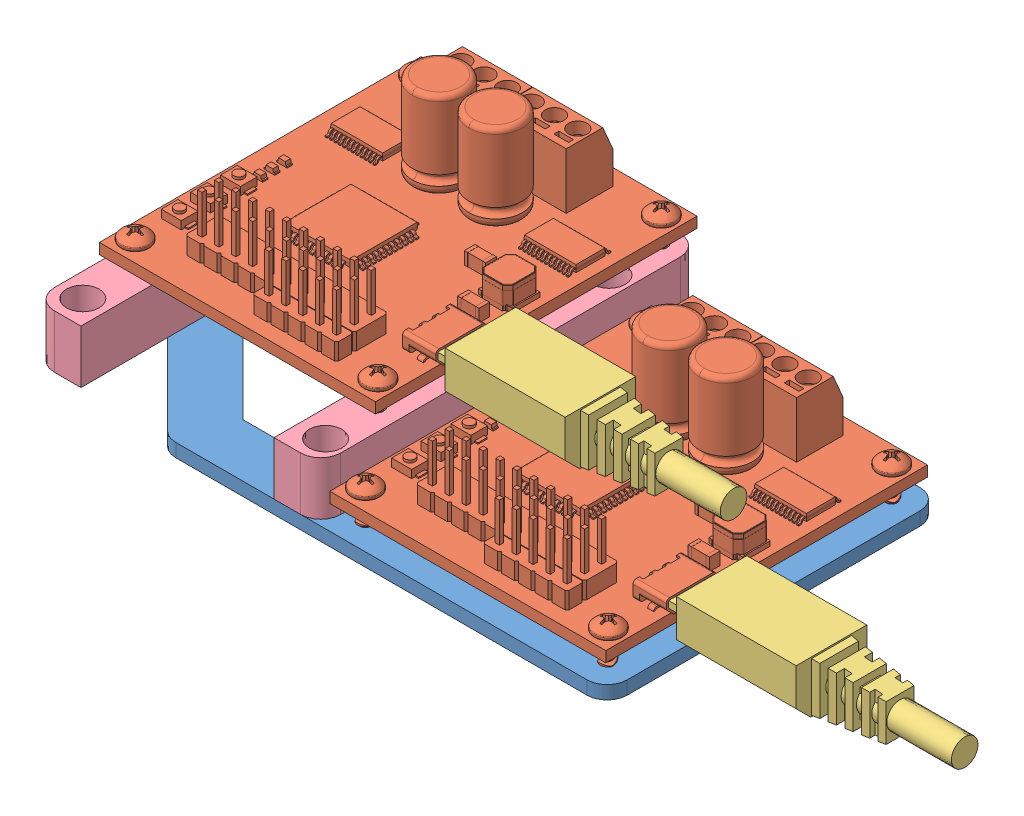
SolidWorks assembly HEL-03-01006-00, configuration Standard. Lengths in mm.
Overall size (126.47 26.64 57).
9 component instances, 5 part files, 22 mates.
Components (placement in the parent):
- HEL-04-01009-01-1: HEL-04-01009-01 [Standard] at origin size (86 2 50)
- HEL-06-01004-00-1: HEL-06-01004-00 [Standard] at (-42.2137 -25.9955 -67.8693) size (41.97 19.44 48.28)
- HEL-06-01004-00-2: HEL-06-01004-00 [Standard] at (0.2353 -33.1955 -60.012) size (41.97 19.44 48.28)
- HEL-06-03005-00-1: HEL-06-03005-00 [Default] at (38.9712 8.625 8.3927) x (0 0 1) z (1 0 0) size (10.6 7.8 44.5)
- HEL-04-01017-01-1: HEL-04-01017-01 [Default] at (-21.5 10 -3.5) x (0 0 1) z (1 0 0) size (57 8 43)
- HEL-06-03005-00-2: HEL-06-03005-00 [Default] at (-3.4778 15.825 0.6353) x (0 0 1) z (1 0 0) size (10.6 7.8 44.5)
- Screw from Motor Controller Kit-1: Screw from Motor Controller Kit [Default] at (-3 4.5 21.27) x (0 -1 0) z (0.932995 0 -0.359891) size (5.92 3.9 3.9)
- Screw from Motor Controller Kit-2: Screw from Motor Controller Kit [Default] at (-3 4.5 -21.28) x (0 -1 0) z (0.932995 0 -0.359891) size (5.92 3.9 3.9)
- Screw from Motor Controller Kit-3: Screw from Motor Controller Kit [Default] at (-39.45 4.5 -21.28) x (0 -1 0) z (0.772196 0 -0.635384) size (5.92 3.9 3.9)
Mates (geometry in assembly coordinates):
- Parallel1: parallel aligned: plane of HEL-06-01004-00-1 through (-42.2137 -25.9955 -67.8693) normal (1 0 0)
- Konzentrisch3: concentric aligned: cylinder of HEL-04-01009-01-1 through (3 2 -21.275) axis (0 1 0) radius 0.8; circle of HEL-06-01004-00-2
- Deckungsgleich3: distance = 1.3 mm anti-aligned: plane of HEL-04-01009-01-1 through (0 2 0) normal (0 1 0); plane of HEL-06-01004-00-2 through (27.2246 3.3 15.777) normal (0 -1 0)
- Parallel2: parallel aligned: plane of HEL-06-01004-00-2 through (0.2353 -33.0955 -60.012) normal (1 0 0)
- Coincident1: coincident anti-aligned: plane of HEL-06-01004-00-2 through (42.4712 6.925 14.2855) normal (0 1 0); plane of micro_usb_plug-1 through (45.4712 6.925 8.3927) normal (0 -1 0)
- Coincident2: coincident anti-aligned: plane of HEL-06-01004-00-2 through (38.9712 6.925 15.2927) normal (1 0 0); plane of micro_usb_plug-1 through (38.9712 8.725 8.3927) normal (-1 0 0)
- Coincident3: coincident anti-aligned: plane of HEL-06-01004-00-2 through (42.4712 7.9321 8.3927) normal (0 0 1); plane of micro_usb_plug-1 through (45.4712 8.725 8.3927) normal (0 0 -1)
- Distance1: distance = 1.0089 mm anti-aligned: plane of HEL-06-01004-00-1 through (-0.5045 11.95 -32) normal (1 0 0); plane of HEL-06-01004-00-2 through (0.5045 4.75 24.1377) normal (-1 0 0)
- Coincident6: coincident aligned: plane of HEL-04-01009-01-1 through (-43 2 -25) normal (-1 0 0); plane of HEL-04-01017-01-1 through (-43 2 -32) normal (-1 0 0)
- Coincident8: coincident anti-aligned: plane of HEL-04-01009-01-1 through (0 2 0) normal (0 1 0); plane of HEL-04-01017-01-1 through (-21.5 2 -3.5) normal (0 -1 0)
- Coincident9: coincident anti-aligned: plane of HEL-06-01004-00-1 through (0.0222 14.025 6.4282) normal (0 1 0); plane of micro_usb_plug-2 through (3.0222 14.025 0.6353) normal (0 -1 0)
- Coincident10: coincident anti-aligned: plane of HEL-06-01004-00-1 through (-3.4778 14.025 7.4353) normal (1 0 0); plane of micro_usb_plug-2 through (-3.4778 15.825 0.6353) normal (-1 0 0)
- Coincident11: coincident anti-aligned: plane of HEL-06-01004-00-1 through (-3.4778 15.0321 7.4353) normal (0 0 -1); plane of micro_usb_plug-2 through (3.0222 15.825 7.4353) normal (0 0 1)
- Coincident12: coincident aligned: plane of HEL-04-01009-01-1 through (-43 2 25) normal (0 0 1); plane of HEL-04-01017-01-1 through (-43 2 25) normal (0 0 1)
- Coincident13: coincident aligned: plane of HEL-06-01004-00-1 through (-41.9445 11.95 -32) normal (0 0 -1); plane of HEL-04-01017-01-1 through (-43 2 -32) normal (0 0 -1)
- Distance3: distance = 0.5 mm anti-aligned: plane of HEL-06-01004-00-1 through (-33.0044 10.5 10.4597) normal (0 -1 0); plane of HEL-04-01017-01-1 through (-21.5 10 -3.5) normal (0 1 0)
- Concentric1: concentric anti-aligned: cylinder of HEL-04-01017-01-1 through (-3 10 21.27) axis (0 1 0) radius 1.45; cylinder of HEL-05-03000-00-1 through (-3 0 21.27) axis (0 -1 0) radius 1.1
- Coincident14: coincident anti-aligned: plane of HEL-04-01017-01-1 through (-3 4.5 22.72) normal (0 1 0); plane of HEL-05-03000-00-1 through (-3.7018 4.5 19.4507) normal (0 -1 0)
- Concentric2: concentric anti-aligned: cylinder of HEL-04-01017-01-1 through (-3 10 -21.28) axis (0 1 0) radius 1.45; cylinder of HEL-05-03000-00-2 through (-3 0 -21.28) axis (0 -1 0) radius 1.1
- Coincident15: coincident anti-aligned: plane of HEL-04-01017-01-1 through (-3 4.5 -19.83) normal (0 1 0); plane of HEL-05-03000-00-2 through (-3.7018 4.5 -23.0993) normal (0 -1 0)
- Concentric3: concentric anti-aligned: cylinder of HEL-04-01017-01-1 through (-39.45 10 -21.28) axis (0 1 0) radius 1.45; cylinder of HEL-05-03000-00-3 through (-39.45 0 -21.28) axis (0 -1 0) radius 1.1
- Coincident16: coincident anti-aligned: plane of HEL-04-01017-01-1 through (-39.45 4.5 -19.83) normal (0 1 0); plane of HEL-05-03000-00-3 through (-40.689 4.5 -22.7858) normal (0 -1 0)
